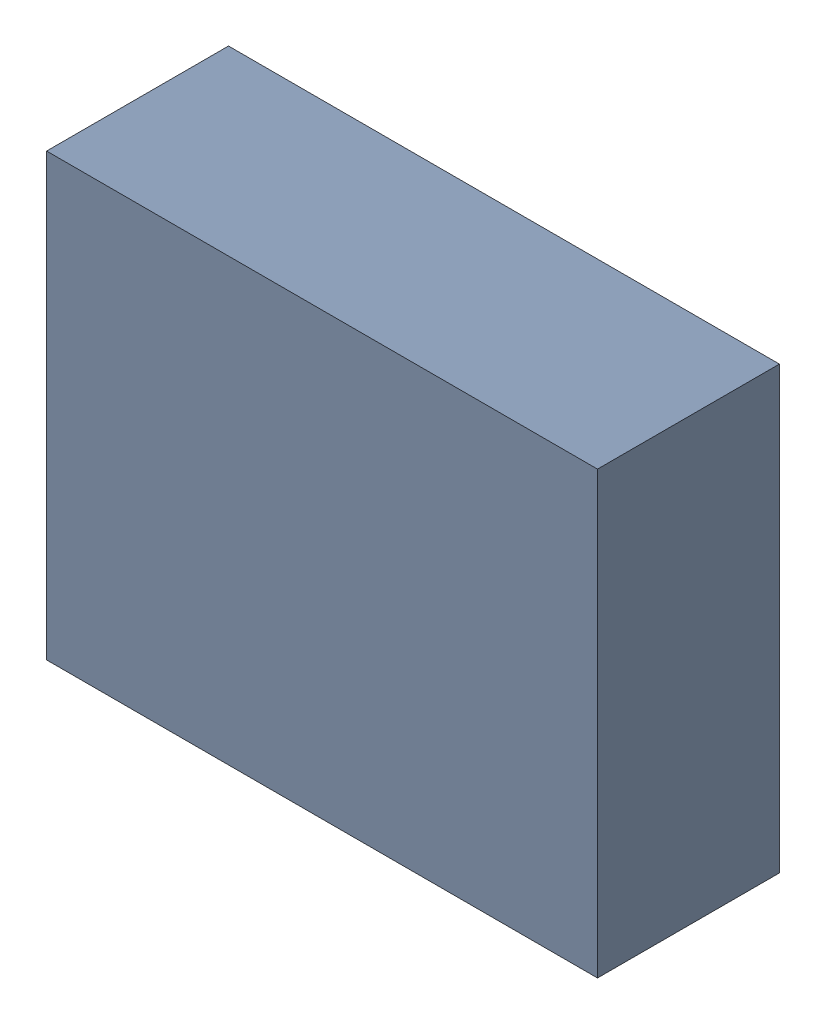
SolidWorks assembly USB67_U2, configuration Default. Lengths in mm.
Overall size (5 4 1.65).
2 component instances, 1 part files, 0 mates.
Components (placement in the parent):
- 402662672-1: 402662672 [Default] at (145.356 84.836 -2.8544) size (5 4 1.65)
  - Extruded_31-1: Extruded_31 [Default] at origin size (5 4 1.65)
